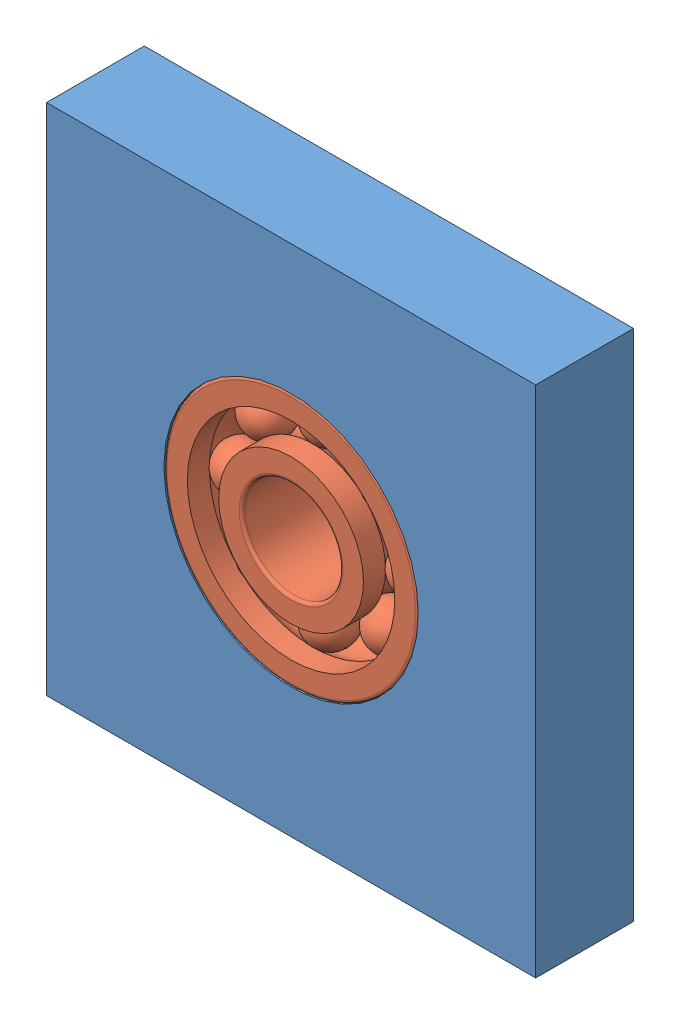
SolidWorks assembly Lagerklotz, configuration Standard. Lengths in mm.
Overall size (50 52.5 10).
2 component instances, 2 part files, 2 mates.
Components (placement in the parent):
- Lagerklotz-1: Lagerklotz [Standard] at (-89.1989 -26.6804 47.5) size (50 52.5 10)
- radial ball bearing_68_din-1: radial ball bearing_68_din [DIN 625 - 6000 - 8,DE,NC,8_68] at (-64.1989 -0.4304 53.5) x (0 0 -1) z (1 0 0) size (8 26 26)
Mates (geometry in assembly coordinates):
- Konzentrisch1: concentric anti-aligned: cylinder of Lagerklotz-1 through (-64.1989 -0.4304 49.5) axis (0 0 1) radius 13; cylinder of radial ball bearing_68_din-1 through (-64.1989 -0.4304 74.1375) axis (0 0 -1) radius 13
- Deckungsgleich1: coincident anti-aligned: plane of Lagerklotz-1 through (-64.1989 -0.4304 49.5) normal (0 0 1); plane of radial ball bearing_68_din-1 through (-64.1989 12.2696 49.5) normal (0 0 -1)
